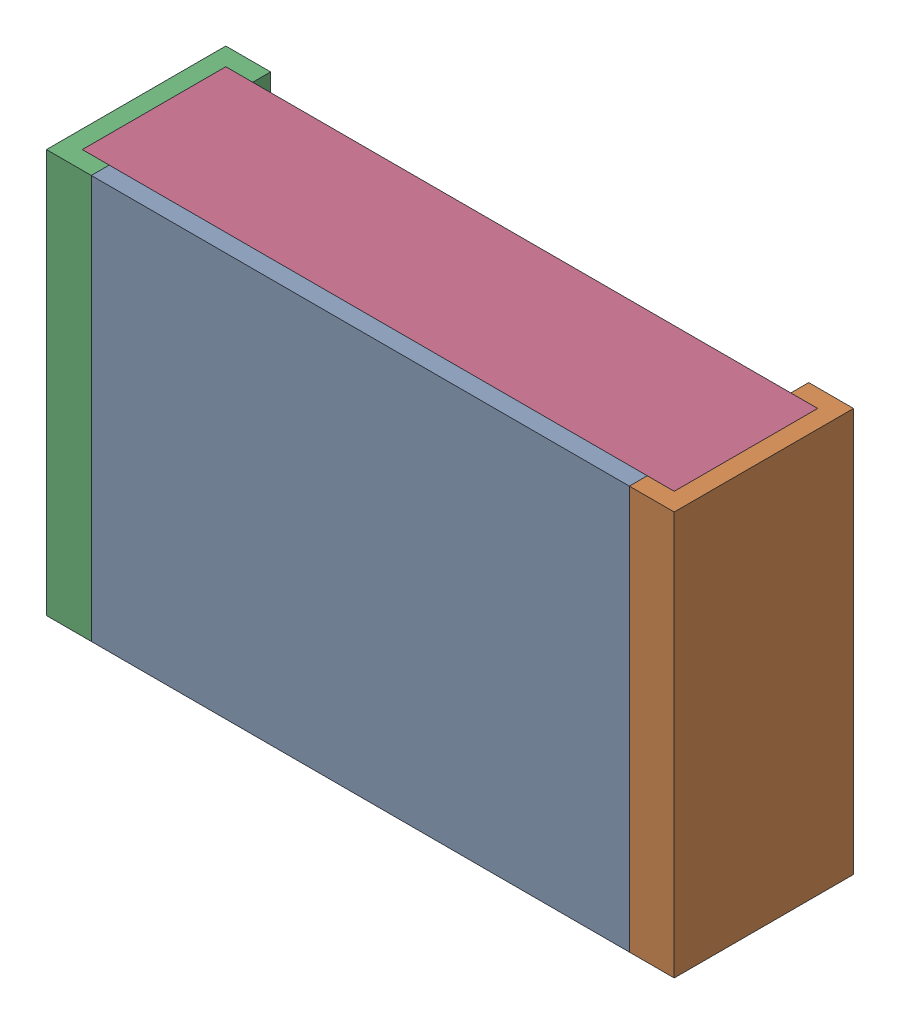
SolidWorks assembly RESC2012X06N.step-2, configuration По умолчанию. Lengths in mm.
Overall size (2.1 1.35 0.6).
4 component instances, 3 part files, 0 mates.
Components (placement in the parent):
- RESC2012X06N.step-Part-1-1: RESC2012X06N.step-Part-1 [По умолчанию] at (-0.9 -0.675 0.54) size (1.8 1.35 0.06)
- RESC2012X06N.step-Part-2-1: RESC2012X06N.step-Part-2 [По умолчанию] at (1.05 0.675 0) x (-1 0 0) z (0 0 1) size (0.15 1.35 0.6)
- RESC2012X06N.step-Part-2-2: RESC2012X06N.step-Part-2 [По умолчанию] at (-1.05 -0.675 0) size (0.15 1.35 0.6)
- RESC2012X06N.step-Part-3-1: RESC2012X06N.step-Part-3 [По умолчанию] at (-1.05 -0.675 0) size (1.98 1.35 0.48)
